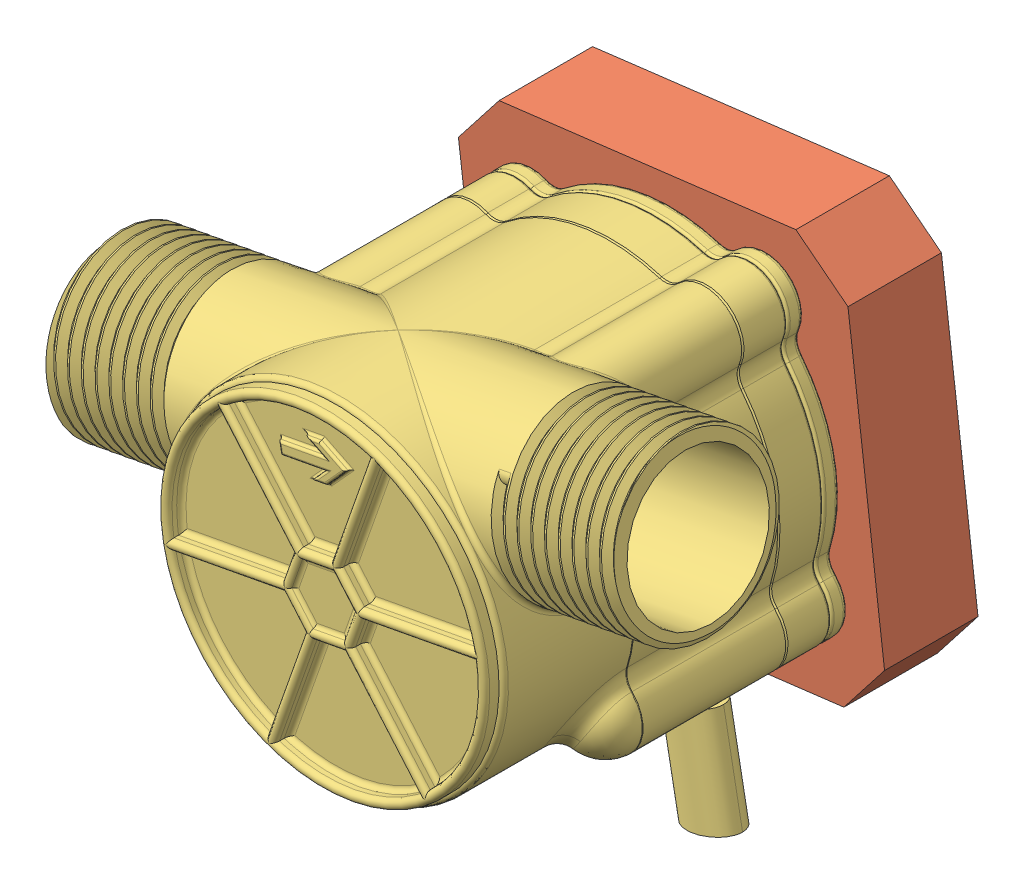
SolidWorks assembly ITEMS Flow Sensor Assembly, configuration Default. Lengths in mm.
Overall size (70.83 64.06 47.5).
9 component instances, 5 part files, 6 mates.
Components (placement in the parent):
- Flow Sensor Mount-1: Flow Sensor Mount [Default] at (-26.0452 -26.4554 15.7) size (70 42 41.5) (hidden)
- 5972K222_Ball Bearing-1: 5972K222_Ball Bearing [5972K222] at (-26.0452 3.5446 36.7) x (0.999821 0.018925 0) z (0 0 1) size (22 22 7)
- Flow Sensor RotatorSLDPRT-1: Flow Sensor RotatorSLDPRT [Default] at (-26.0452 3.5446 43.2) x (-0.992495 -0.122282 0) z (0.122282 -0.992495 0) size (42 10 42)
- Water Flow sensor.STEP-1: Water Flow sensor.STEP [Default] at (-73.8325 -35.4155 63.3705) x (-0.98278 -0.18478 0) z (-0.18478 0.98278 0) size (62.01 39.49 53.53)
  - Water Flow Sensor.STEP-1: Water Flow Sensor.STEP [Default] at (-54.2965 -20.1705 29.9446) size (62.01 39 53.53)
  - pan cross head_ai_CR-PHMS 0.112-48x0.375x0.375-S.STEP-1: pan cross head_ai_CR-PHMS 0.112-48x0.375x0.375-S.STEP [Default] at (-67.0244 -22.2025 42.6725) x (0 1 0) z (0 0 1) size (11.52 5.56 5.56)
  - pan cross head_ai_CR-PHMS 0.112-48x0.375x0.375-S.STEP-2: pan cross head_ai_CR-PHMS 0.112-48x0.375x0.375-S.STEP [Default] at (-67.0244 -22.2025 17.2167) x (0 1 0) z (0 0 1) size (11.52 5.56 5.56)
  - pan cross head_ai_CR-PHMS 0.112-48x0.375x0.375-S.STEP-3: pan cross head_ai_CR-PHMS 0.112-48x0.375x0.375-S.STEP [Default] at (-41.5686 -22.2025 17.2167) x (0 1 0) z (0 0 1) size (11.52 5.56 5.56)
  - pan cross head_ai_CR-PHMS 0.112-48x0.375x0.375-S.STEP-4: pan cross head_ai_CR-PHMS 0.112-48x0.375x0.375-S.STEP [Default] at (-41.5686 -22.2025 42.6725) x (0 1 0) z (0 0 1) size (11.52 5.56 5.56)
Mates (geometry in assembly coordinates):
- Coincident1: coincident anti-aligned: plane of Flow Sensor Mount-1 through (-61.0452 -24.4554 33.2) normal (0 0 1); plane of 5972K222_Ball Bearing-1 through (-26.2468 14.1927 33.2) normal (0 0 -1)
- Concentric1: concentric aligned: circle of Flow Sensor Mount-1; cylinder of 5972K222_Ball Bearing-1 through (-26.0452 3.5446 40.2) axis (0 0 1) radius 4
- Coincident3: coincident anti-aligned: plane of Flow Sensor Mount-1 through (-61.0452 -24.4554 33.2) normal (0 0 1); plane of Flow Sensor RotatorSLDPRT-1 through (-26.0452 3.5446 33.2) normal (0 0 -1)
- Concentric2: concentric aligned: circle of 5972K222_Ball Bearing-1; circle of Flow Sensor RotatorSLDPRT-1
- Coincident4: coincident anti-aligned: plane of Flow Sensor RotatorSLDPRT-1 through (-26.0452 3.5446 43.2) normal (0 0 1); plane of Water Flow sensor.STEP-1/Water Flow Sensor.STEP-1 through (-26.0041 4.0464 43.2) normal (0 0 -1)
- Concentric3: concentric aligned: circle of Flow Sensor RotatorSLDPRT-1; circle of Water Flow sensor.STEP-1/Water Flow Sensor.STEP-1
